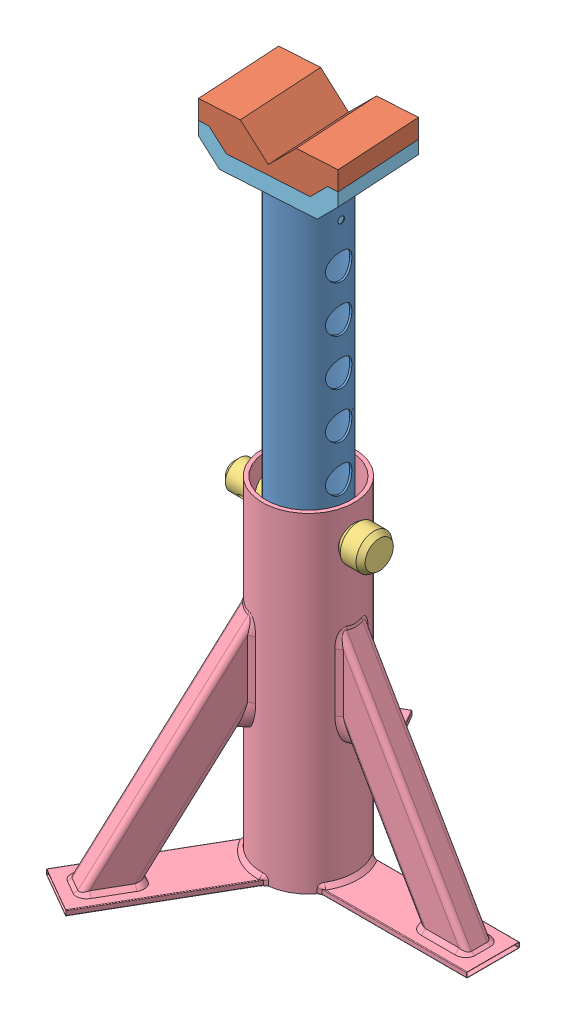
SolidWorks assembly Ensamblaje1, configuration Predeterminado. Lengths in mm.
Overall size (227.32 491.63 262.49).
5 component instances, 5 part files, 8 mates.
Components (placement in the parent):
- Pieza15-1: Pieza15 [Predeterminado<Como mecanizada>] at (0 452 0) x (0 1 0) z (1 0 0) size (300 50 50)
- Pieza17-1: Pieza17 [Predeterminado] at (0 464.6141 0) x (0.998124 0 -0.061227) z (0.061227 0 0.998124) size (100 27 65)
- Pieza18-1: Pieza18 [Predeterminado] at (-52.3142 233.9892 5.7882) x (1 0 0) z (0 -0.54138 0.840778) size (110 27.18 27.18)
- Pieza14-1: Pieza14 [Predeterminado<Como mecanizada>] at origin size (227.32 250.02 262.49)
- Pieza16-1: Pieza16 [Predeterminado] at (0 464.6141 0) x (0.998124 0 -0.061227) z (0.061227 0 0.998124) size (100 55 65)
Mates (geometry in assembly coordinates):
- Coincidente1: coordinate: point of Pieza14-1; point of assembly
- Concéntrica1: concentric aligned: cylinder of Pieza18-1 through (-56.3142 225 0) axis (-1 0 0) radius 10.6915; cylinder of Pieza14-1 through (40 225 0) axis (-1 0 0) radius 10
- Concéntrica3: concentric anti-aligned: cylinder of Pieza15-1 through (0 152 0) axis (0 1 0) radius 25; cylinder of Pieza14-1 through (0 250 0) axis (0 -1 0) radius 32
- Concéntrica4: concentric anti-aligned: cylinder of Pieza15-1 through (-25 225 0) axis (1 0 0) radius 10; cylinder of Pieza14-1 through (40 225 0) axis (-1 0 0) radius 10
- Concéntrica5: concentric anti-aligned: cylinder of Pieza15-1 through (0 152 0) axis (0 1 0) radius 23.5; cylinder of Pieza16-1 through (0 422.1141 0) axis (0 -1 0) radius 24.5
- Coincidente4: coincident aligned: plane of Pieza17-1 through (-47.9163 477.1141 35.5004) normal (-0.998124 0 0.061227); plane of Pieza16-1 through (-47.9163 477.1141 35.5004) normal (-0.998124 0 0.061227)
- Coincidente5: coincident aligned: plane of Pieza17-1 through (1.9899 464.6141 32.439) normal (0.061227 0 0.998124); plane of Pieza16-1 through (1.9899 464.6141 32.439) normal (0.061227 0 0.998124)
- Coincidente6: coincident anti-aligned: plane of Pieza17-1 through (-27.9538 464.6141 34.2758) normal (0 -1 0); plane of Pieza16-1 through (-27.9538 464.6141 34.2758) normal (0 1 0)
